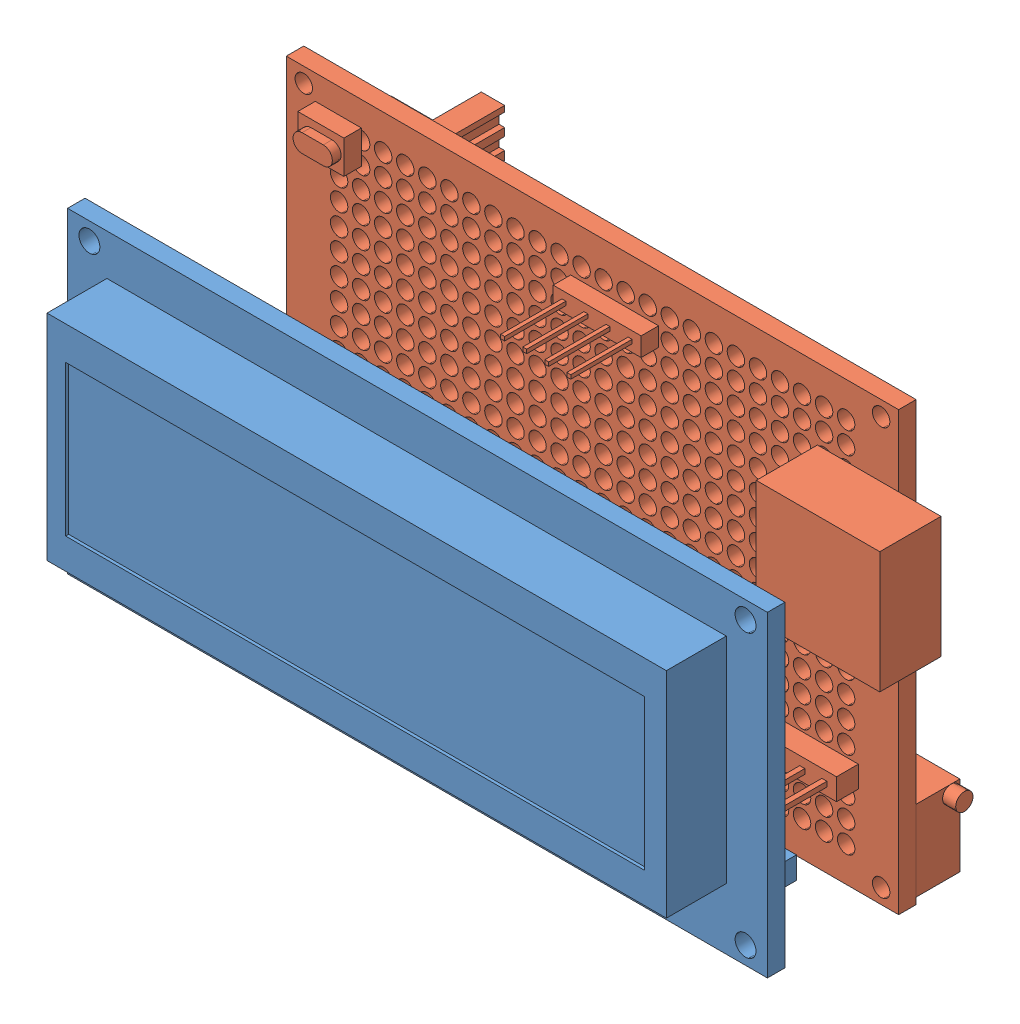
SolidWorks assembly 装配体2, configuration 默认. Lengths in mm.
Overall size (80 50 40.69).
2 component instances, 2 part files, 2 mates.
Components (placement in the parent):
- 延时开关-电路板-1602LED-1: 延时开关-电路板-1602LED [默认] at (-132.6914 36.9671 -11.0864) size (80 36.2 17.17)
- 延时开关-电路板-主板-1: 延时开关-电路板-主板 [默认] at (-167.9492 18.9993 -31.926) x (1 0 0) z (0 0 -1) size (74.84 50 20.5)
Mates (geometry in assembly coordinates):
- 重合29: coincident anti-aligned: plane of 延时开关-电路板-1602LED-1 through (-173.6617 7.7356 -19.4064) normal (1 0 0); plane of 延时开关-电路板-主板-1 through (-173.6617 6.9869 -22.426) normal (-1 0 0)
- 重合30: coincident aligned: plane of 延时开关-电路板-1602LED-1 through (-133.7834 8.5587 -19.4064) normal (0 1 0); plane of 延时开关-电路板-主板-1 through (-174.6747 8.5587 -29.426) normal (0 1 0)
